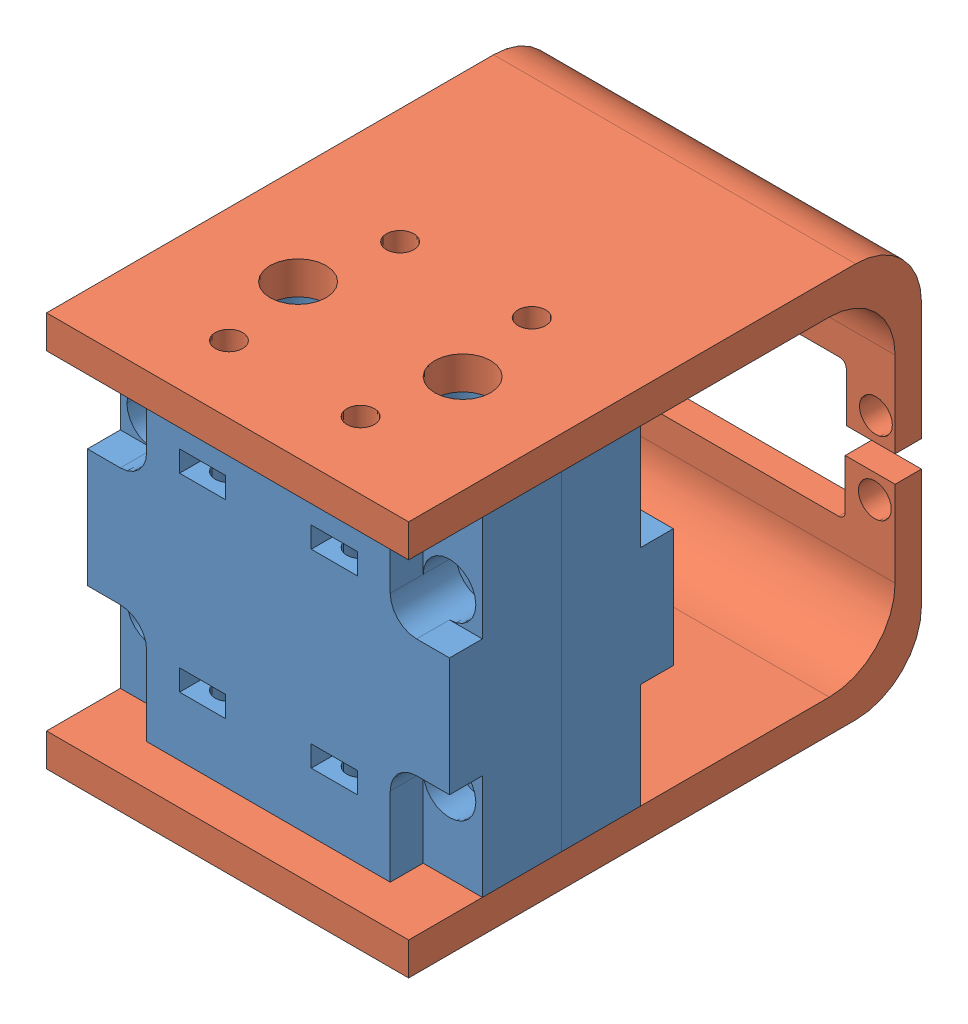
SolidWorks assembly Elevator, configuration Default. Lengths in mm.
Overall size (55 60 77.9).
4 component instances, 2 part files, 7 mates.
Components (placement in the parent):
- guidage-1: guidage [Défaut] at (7.2529 36.9069 40.1491) size (55 50 17)
- guidage-2: guidage [Défaut] at (7.2529 36.9069 64.1491) x (-1 0 0) z (0 0 -1) size (55 50 17)
- CHDENLOUTA-1: CHDENLOUTA [Default] at (7.1705 6.9069 51.6293) x (1 0 0) z (0 1 0) size (55 77.9 28)
- CHDENLOUTA-3: CHDENLOUTA [Default] at (7.3353 66.9069 51.6293) x (-1 0 0) z (0 -1 0) size (55 77.9 28)
Mates (geometry in assembly coordinates):
- Coincident1: coincident anti-aligned: plane of guidage-1 through (7.2529 36.9069 52.1491) normal (0 0 1); plane of guidage-2 through (7.2529 36.9069 52.1491) normal (0 0 -1)
- Coincident2: coincident aligned: plane of guidage-1 through (-5.2471 61.9069 52.1491) normal (0 1 0); plane of guidage-2 through (19.7529 61.9069 52.1491) normal (0 1 0)
- Concentric1: concentric anti-aligned: cylinder of guidage-1 through (29.7529 49.9069 35.1491) axis (0 0 1) radius 2.1; cylinder of guidage-2 through (29.7529 49.9069 69.1491) axis (0 0 -1) radius 2.1
- Concentric2: concentric aligned: cylinder of guidage-1 through (-15.2471 23.9069 45.1491) axis (0 0 -1) radius 4; cylinder of guidage-2 through (-15.2471 23.9069 69.1491) axis (0 0 -1) radius 2.1
- Coincident4: coincident anti-aligned: plane of guidage-2 through (-5.2471 11.9069 52.1491) normal (0 -1 0); plane of CHDENLOUTA-1 through (7.2529 11.9069 140.3568) normal (0 1 0)
- Coaxiale3: concentric anti-aligned: circle of guidage-1; cylinder of CHDENLOUTA-1 through (19.7529 11.9069 52.1491) axis (0 -1 0) radius 4.25
- Coaxiale4: concentric aligned: circle of guidage-2; circle of CHDENLOUTA-1
